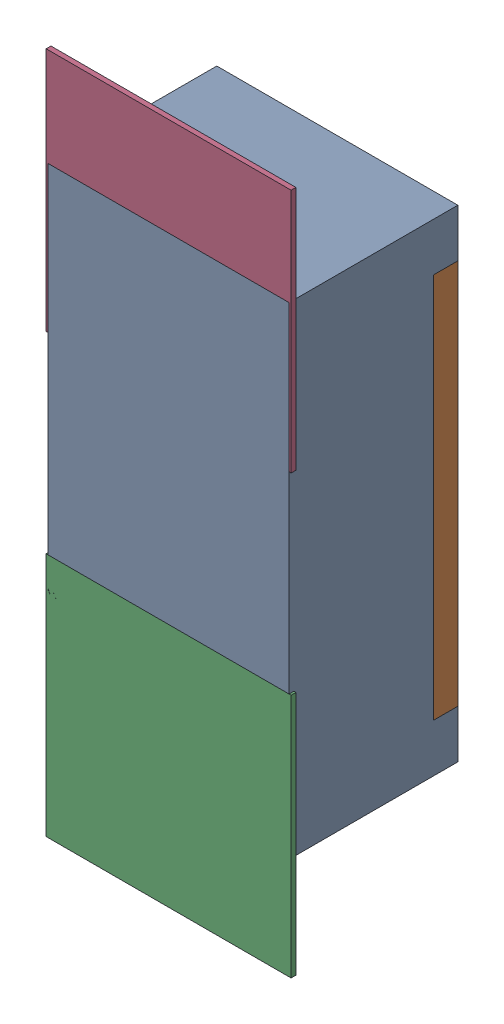
SolidWorks assembly R65, configuration Défaut. Lengths in mm.
Overall size (0.51 1.42 0.35).
5 component instances, 2 part files, 0 mates.
Components (placement in the parent):
- R0402-1: R0402 [Défaut] at (40.115 -45.6168 -2.0818) x (0 1 0) z (0 0 -1) size (1 0.5 0.35)
- 6504207776-1: 6504207776 [Défaut] at (40.1151 -46.0739 -2.0918) size (0.51 0.51 0.01)
  - Extruded-1: Extruded [Défaut] at origin size (0.51 0.51 0.01)
- 6504207776-2: 6504207776 [Défaut] at (40.1151 -45.1668 -2.0918) size (0.51 0.51 0.01)
  - Extruded-1: Extruded [Défaut] at origin size (0.51 0.51 0.01)
